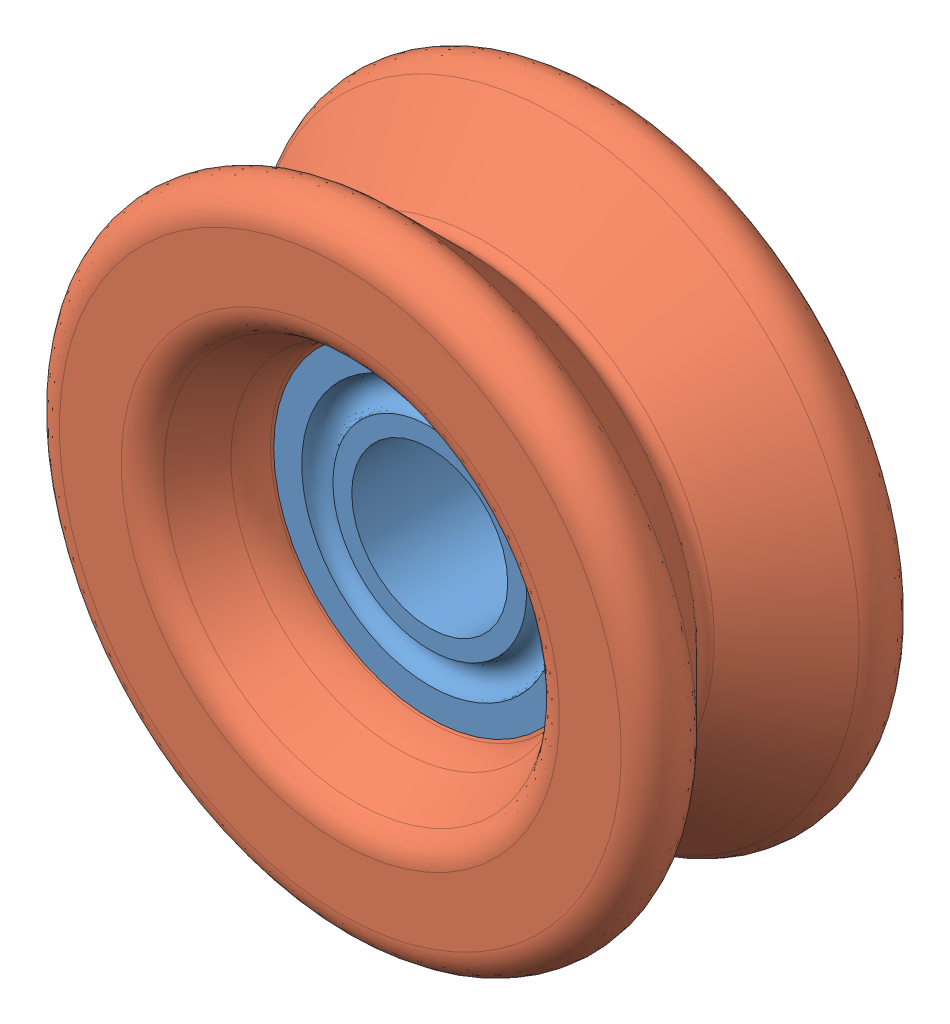
SolidWorks assembly BearingStringGuideAssem, configuration Default. Lengths in mm.
Overall size (25.4 25.4 10.96).
2 component instances, 2 part files, 4 mates.
Components (placement in the parent):
- Sparkfun_FlangedBallBearing_13012-2: Sparkfun_FlangedBallBearing_13012 [Default] at origin size (13.89 13.89 4.7)
- StringGuideWheel-1: StringGuideWheel [Default] x (0 0 -1) z (1 0 0) size (10.96 25.4 25.4)
Mates (geometry in assembly coordinates):
- InPlace2: in place: plane of StringGuideWheel-1 through (0 0 0) normal (1 0 0); moOrthogonalPlaneRef_w of StringGuideWheel-1 through (0 0 0) normal (0 1 0); plane of StringGuideWheel-1 through (0 0 0) normal (0 0 -1); unknown of StringGuideWheel-1
- Coincident4: coincident aligned: 
- Coincident5: coincident aligned: plane of StringGuideWheel^BearingStringGuideAssem-1 through (0 0 0) normal (0 1 0)
- Coincident6: coincident anti-aligned: plane of StringGuideWheel^BearingStringGuideAssem-1 through (0 0 0) normal (0 0 -1)
